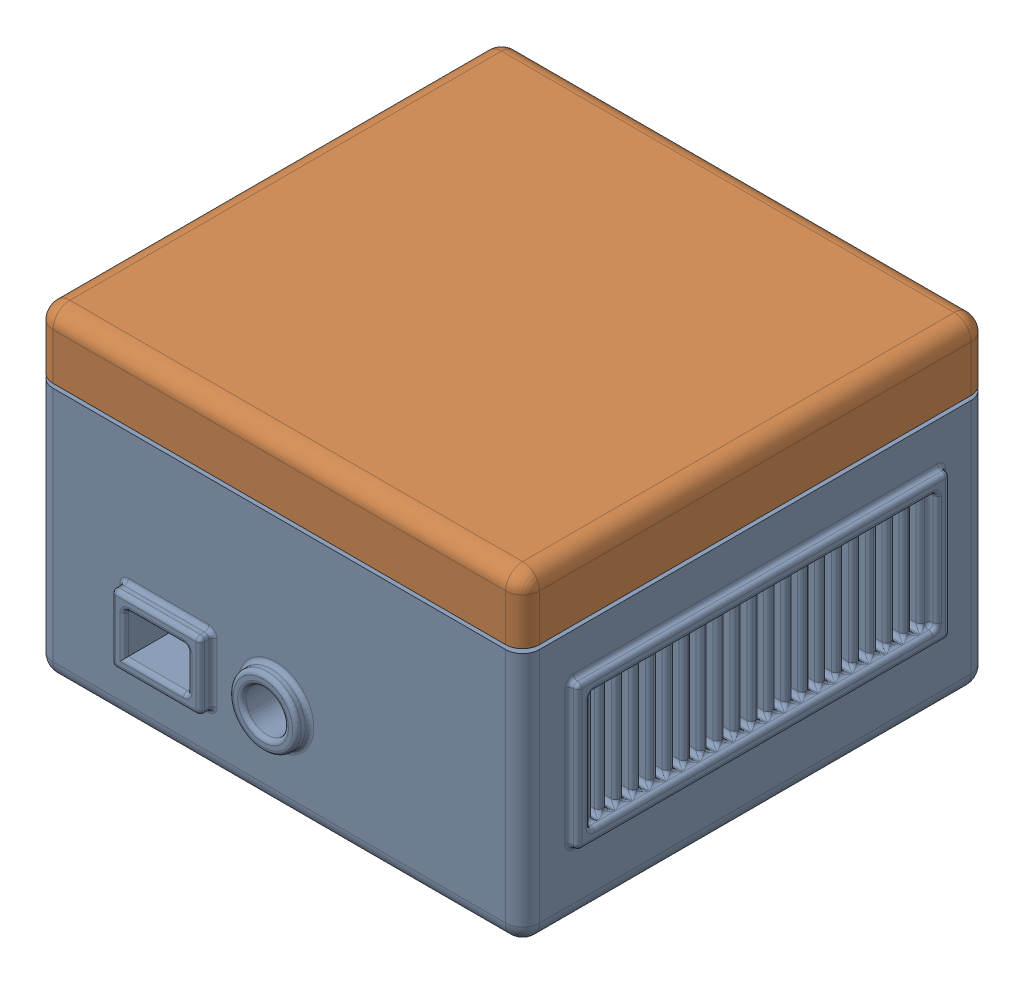
SolidWorks assembly hydro system, configuration Default. Lengths in mm.
Overall size (117 76 113).
2 component instances, 2 part files, 3 mates.
Components (placement in the parent):
- bottom hydro-1: bottom hydro [Default] at (-26.9504 -1.4264 15.1904) size (117 60 113)
- top hydro-1: top hydro [Default] at (51.031 74.5736 56.2918) x (-1 0 0) z (0 0 1) size (115 25 110)
Mates (geometry in assembly coordinates):
- Width1: width aligned: plane of top hydro-1 through (72.1662 59.5736 110.1904) normal (0 0 1); plane of bottom hydro-1 through (72.1662 59.5736 0.1904) normal (0 0 -1); plane of top hydro-1 through (-42.8338 13.5736 110.1904) normal (0 0 1); plane of bottom hydro-1 through (-42.8338 13.5736 0.1904) normal (0 0 -1)
- Width2: width anti-aligned: plane of top hydro-1 through (-42.8338 59.5736 110.1904) normal (-1 0 0); plane of bottom hydro-1 through (72.1662 59.5736 110.1904) normal (1 0 0); plane of top hydro-1 through (72.1662 13.5736 0.1904) normal (1 0 0); plane of bottom hydro-1 through (-42.8338 13.5736 0.1904) normal (-1 0 0)
- LimitDistance1: limit distance = 1 mm anti-aligned: plane of top hydro-1 through (51.031 59.5736 56.2918) normal (0 -1 0); plane of bottom hydro-1 through (-38.8338 58.5736 106.1904) normal (0 1 0)
